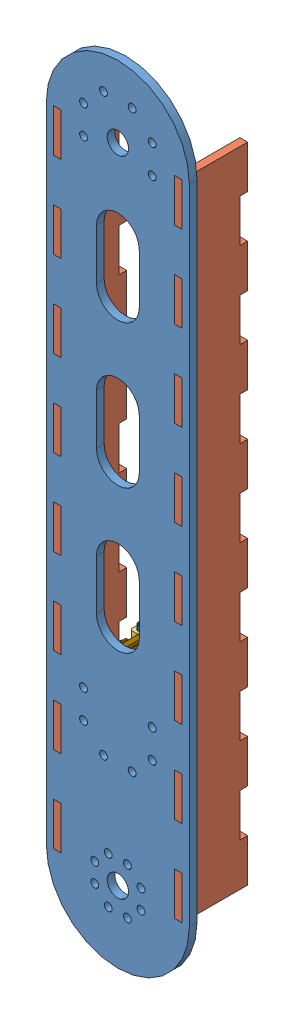
SolidWorks assembly upperarm, configuration Default. Lengths in mm.
Overall size (100 550 49.09).
20 component instances, 10 part files, 10 mates.
Components (placement in the parent):
- ME134 Robot Upper Arm-1: ME134 Robot Upper Arm [Default] at (-2.2193 242.2859 -5.4) x (0 1 0) z (0 0 1) size (550 100 5.4)
- ME134 Arm Flange Short-1: ME134 Arm Flange Short [Default] at (-47.2193 -160.878 -22.1457) x (0 1 0) z (1 0 0) size (450 45.8 5.4)
- ME134 Arm Flange Short-2: ME134 Arm Flange Short [Default] at (37.3807 -160.878 -22.1457) x (0 1 0) z (1 0 0) size (450 45.8 5.4)
- HEBI Gripper Spool-1: HEBI Gripper Spool [Default] at (-2.2185 95.7852 -40.4) x (0.000042 1 0) z (-1 0.000042 0) size (109.71 43.69 73.67)
  - HEBI Robotics-Default (X5-9)_PM-2293-01-1: HEBI Robotics-Default (X5-9)_PM-2293-01 [Default] x (-1 0 0) z (0 0 -1) size (65.4 11.85 69.3)
  - HEBI Robotics-Default (X5-9)_PM-2292-01-1: HEBI Robotics-Default (X5-9)_PM-2292-01 [Default] at (0.0007 -3.95 0.0008) x (-1 0 0) z (0 0 -1) size (50 11 50)
  - HEBI Robotics-Default (X5-9)_PM-2290-01-1: HEBI Robotics-Default (X5-9)_PM-2290-01 [Default] at (-3.2493 3.55 -6.4992) x (-1 0 0) z (0 0 -1) size (15 7 25)
  - HEBI Robotics-Default (X5-9)_PP-2205-35-1: HEBI Robotics-Default (X5-9)_PP-2205-35 [Default] at (-18.09 -34.551 -30) x (0.92376 0 -0.382972) z (0 -1 0) size (5.5 5.5 38.26)
  - HEBI Robotics-Default (X5-9)_PP-2205-35-2: HEBI Robotics-Default (X5-9)_PP-2205-35 [Default] at (30 -34.551 14.91) x (0.92376 0 -0.382972) z (0 -1 0) size (5.5 5.5 38.26)
  - HEBI Robotics-Default (X5-9)_PP-2205-35-3: HEBI Robotics-Default (X5-9)_PP-2205-35 [Default] at (-15.79 -34.551 33.5) x (0.92376 0 -0.382972) z (0 -1 0) size (5.5 5.5 38.26)
  - HEBI Robotics-Default (X5-9)_PP-2205-35-4: HEBI Robotics-Default (X5-9)_PP-2205-35 [Default] at (30 -34.551 -14.91) x (0.92376 0 -0.382972) z (0 -1 0) size (5.5 5.5 38.26)
  - HEBI Robotics-Default (X5-9)_PP-2205-08-1: HEBI Robotics-Default (X5-9)_PP-2205-08 [Default] at (-6.7493 -2.45 -6.4992) x (0.940312 0 -0.340315) z (0 -1 0) size (5.5 5.5 11.2)
  - HEBI Robotics-Default (X5-9)_PP-2205-08-2: HEBI Robotics-Default (X5-9)_PP-2205-08 [Default] at (0.2507 -2.45 -14.9992) x (0.940312 0 -0.340315) z (0 -1 0) size (5.5 5.5 11.2)
  - HEBI Robotics-Default (X5-9)_PP-2205-08-3: HEBI Robotics-Default (X5-9)_PP-2205-08 [Default] at (0.2507 -2.45 2.0008) x (0.940312 0 -0.340315) z (0 -1 0) size (5.5 5.5 11.2)
  - HEBI Robotics-Default (X5-9)_PP-2131-12(PP-2131-12)-1: HEBI Robotics-Default (X5-9)_PP-2131-12(PP-2131-12) [Default] at (16.2542 -9.95 6.4871) x (-0.985138 0 -0.171764) z (0 -1 0) size (8.5 8.5 17.42)
  - HEBI Robotics-Default (X5-9)_PP-2131-12(PP-2131-12)-2: HEBI Robotics-Default (X5-9)_PP-2131-12(PP-2131-12) [Default] at (-16.0788 -9.95 6.9072) x (-0.985138 0 -0.171764) z (0 -1 0) size (8.5 8.5 17.42)
  - HEBI Robotics-Default (X5-9)_PP-2131-12(PP-2131-12)-3: HEBI Robotics-Default (X5-9)_PP-2131-12(PP-2131-12) [Default] at (16.0802 -9.95 -6.9057) x (-0.985138 0 -0.171764) z (0 -1 0) size (8.5 8.5 17.42)
  - HEBI Robotics-Default (X5-9)_PP-2131-12(PP-2131-12)-4: HEBI Robotics-Default (X5-9)_PP-2131-12(PP-2131-12) [Default] at (-16.2529 -9.95 -6.4855) x (-0.985138 0 -0.171764) z (0 -1 0) size (8.5 8.5 17.42)
  - HEBI Robotics-Default (X5-9)_X5-Export-1: HEBI Robotics-Default (X5-9)_X5-Export [Default] at (0.0007 -20 0.0008) x (-1 0 -0.000042) z (0 1 0) size (109.71 73.14 31.05)
  - HEBI Robotics-Default (X5-9)_PP-2241-01-1: HEBI Robotics-Default (X5-9)_PP-2241-01 [Default] at (20 0 23) x (0 -0.336423 -0.941711) z (0 -0.941711 0.336423) size (5.5 11 5.5)
Mates (geometry in assembly coordinates):
- Width1: width anti-aligned: plane of ME134 Arm Flange Short-1 through (-47.2193 -160.878 -22.1457) normal (-1 0 0); plane of ME134 Robot Upper Arm-1 through (-41.8193 -160.878 -22.1457) normal (1 0 0); plane of ME134 Arm Flange Short-1 through (-47.2193 242.2859 0) normal (1 0 0); plane of ME134 Robot Upper Arm-1 through (-41.8193 242.2859 0) normal (-1 0 0)
- Coincident1: coincident anti-aligned: plane of ME134 Arm Flange Short-1 through (-41.8193 89.7859 -5.4) normal (0 0 1); plane of ME134 Robot Upper Arm-1 through (-2.2193 242.2859 -5.4) normal (0 0 -1)
- Coincident2: coincident anti-aligned: plane of ME134 Robot Upper Arm-1 through (-2.2193 449.7859 0) normal (0 -1 0); plane of ME134 Arm Flange Short-1 through (-41.8193 449.7859 -5.4) normal (0 1 0)
- Coincident3: coincident anti-aligned: plane of ME134 Robot Upper Arm-1 through (-2.2193 242.2859 -5.4) normal (0 0 -1); plane of ME134 Arm Flange Short-2 through (42.7807 149.7859 -5.4) normal (0 0 1)
- Coincident4: coincident anti-aligned: plane of ME134 Robot Upper Arm-1 through (-2.2193 449.7859 0) normal (0 -1 0); plane of ME134 Arm Flange Short-2 through (42.7807 449.7859 -5.4) normal (0 1 0)
- Width3: width anti-aligned: plane of ME134 Arm Flange Short-2 through (37.3807 -160.878 -22.1457) normal (-1 0 0); plane of ME134 Robot Upper Arm-1 through (42.7807 -160.878 -22.1457) normal (1 0 0); plane of ME134 Arm Flange Short-2 through (37.3807 242.2859 0) normal (1 0 0); plane of ME134 Robot Upper Arm-1 through (42.7807 242.2859 0) normal (-1 0 0)
- Coincident5: coincident anti-aligned: plane of ME134 Robot Upper Arm-1 through (-2.2193 242.2859 -5.4) normal (0 0 -1); plane of HEBI Gripper Spool-1/HEBI Robotics-Default (X5-9)_X5-Export-1 through (-2.2193 95.7859 -5.4) normal (0 0 1)
- Concentric1: concentric anti-aligned: cylinder of ME134 Robot Upper Arm-1 through (-26.2193 87.7859 0) axis (0 0 -1) radius 2.75; cylinder of HEBI Gripper Spool-1/HEBI Robotics-Default (X5-9)_X5-Export-1 through (-26.2193 87.7859 -5.4) axis (0 0 1) radius 2.1
- Concentric2: concentric anti-aligned: cylinder of ME134 Robot Upper Arm-1 through (-26.2193 107.7859 0) axis (0 0 -1) radius 2.75; cylinder of HEBI Gripper Spool-1/HEBI Robotics-Default (X5-9)_X5-Export-1 through (-26.2193 107.7859 -5.4) axis (0 0 1) radius 2.1
- Coincident6: coincident aligned: plane of ME134 Robot Upper Arm-1 through (-2.2193 242.2859 0) normal (0 0 1)
